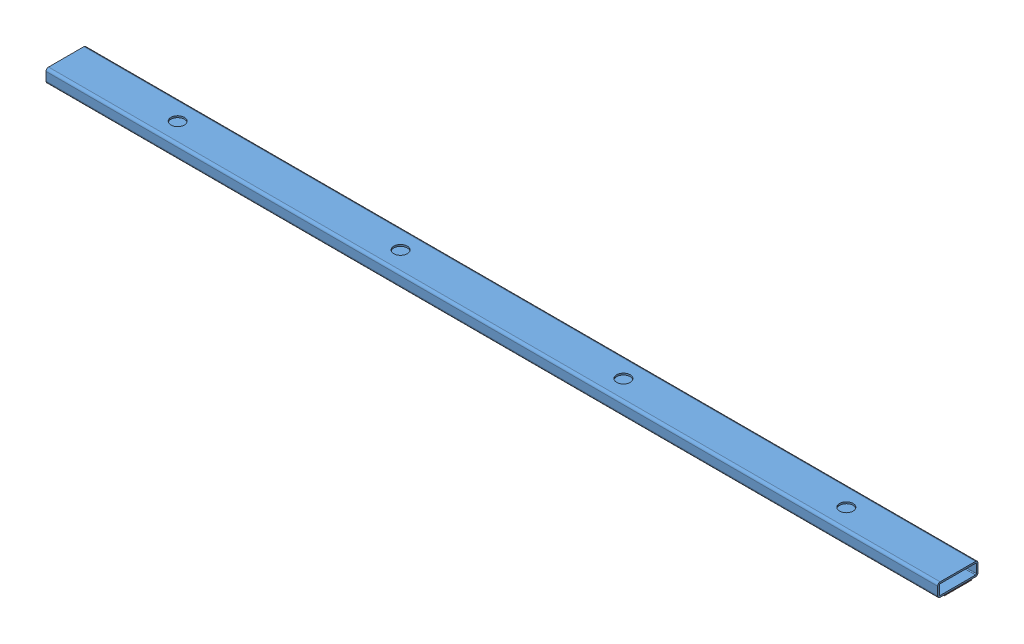
SolidWorks assembly GE-20049, configuration blue. Lengths in mm.
Overall size (1682.75 26.99 76.2).
2 component instances, 2 part files, 6 mates.
Components (placement in the parent):
- GE-20054-1: GE-20054 [GE-20054-blue] at origin size (1682.75 25.4 76.2)
- Hook_2_66-25-1: Hook_2_66-25 [Default] at (-841.375 -1.5875 25.4) size (1682.75 1.59 50.8)
Mates (geometry in assembly coordinates):
- Coincident1: coincident anti-aligned: plane of GE-20054-1 through (841.375 0 -33.3248) normal (0 -1 0); plane of Hook_2_66-25-1 through (-841.375 0 25.4) normal (0 1 0)
- Coincident2: coincident aligned: plane of GE-20054-1 through (841.375 20.6248 -33.3248) normal (1 0 0); plane of Hook_2_66-25-1 through (841.375 0 25.4) normal (1 0 0)
- Width1: width anti-aligned: plane of GE-20054-1 through (841.375 20.6248 38.1) normal (0 0 1); plane of GE-20054-1 through (841.375 20.6248 -38.1) normal (0 0 -1); plane of Hook_2_66-25-1 through (-841.375 0 -25.4) normal (0 0 -1); plane of Hook_2_66-25-1 through (-841.375 0 25.4) normal (0 0 1)
- Coincident3: coincident aligned: plane of GE-20054-1 through (0 0 0) normal (0 0 1)
- Coincident4: coincident aligned: plane of GE-20054-1 through (0 0 0) normal (0 1 0)
- Coincident5: coincident aligned: plane of GE-20054-1 through (0 0 0) normal (1 0 0)
